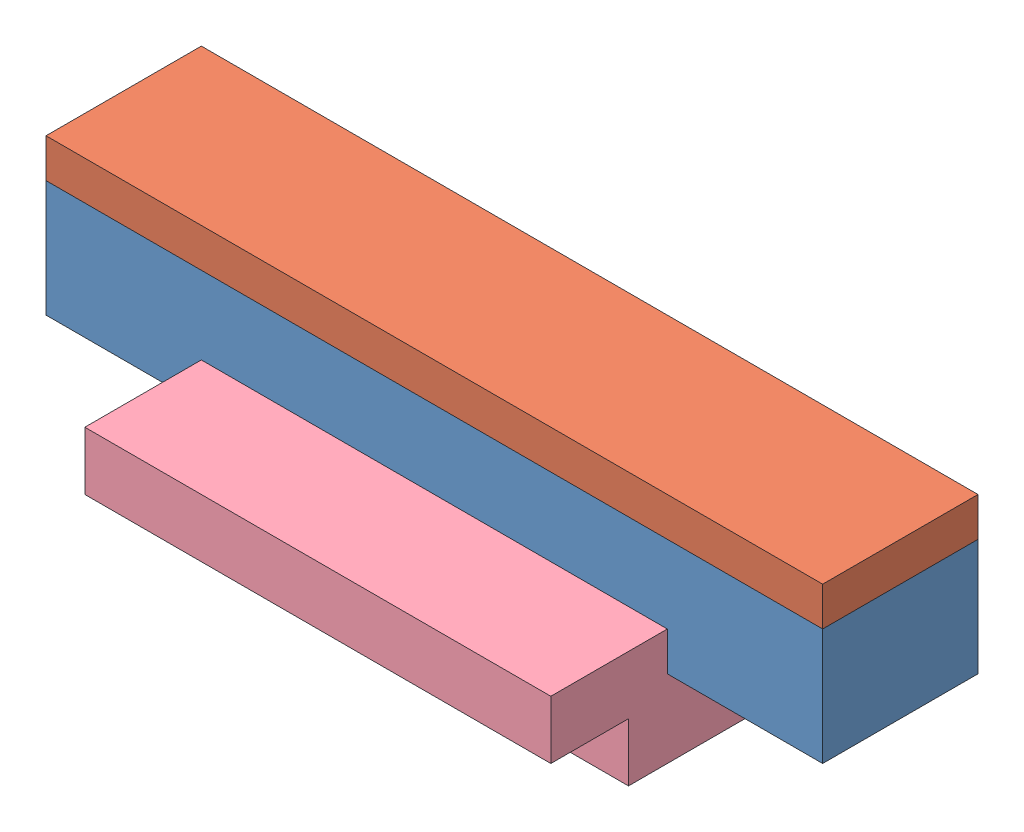
SolidWorks assembly 人脸识别支架, configuration 默认. Lengths in mm.
Overall size (100 35 40).
4 component instances, 4 part files, 0 mates.
Components (placement in the parent):
- 主体外壳-1: 主体外壳 [默认] at origin size (100 15 20)
- 前面板-1: 前面板 [默认] at origin size (100 5 20)
- PCB台-1: PCB台 [默认] at origin size (60 30 5)
- 零件3-1: 零件3 [默认] at (0.0892 -0.0878 -0.0042) size (60 15 25)
